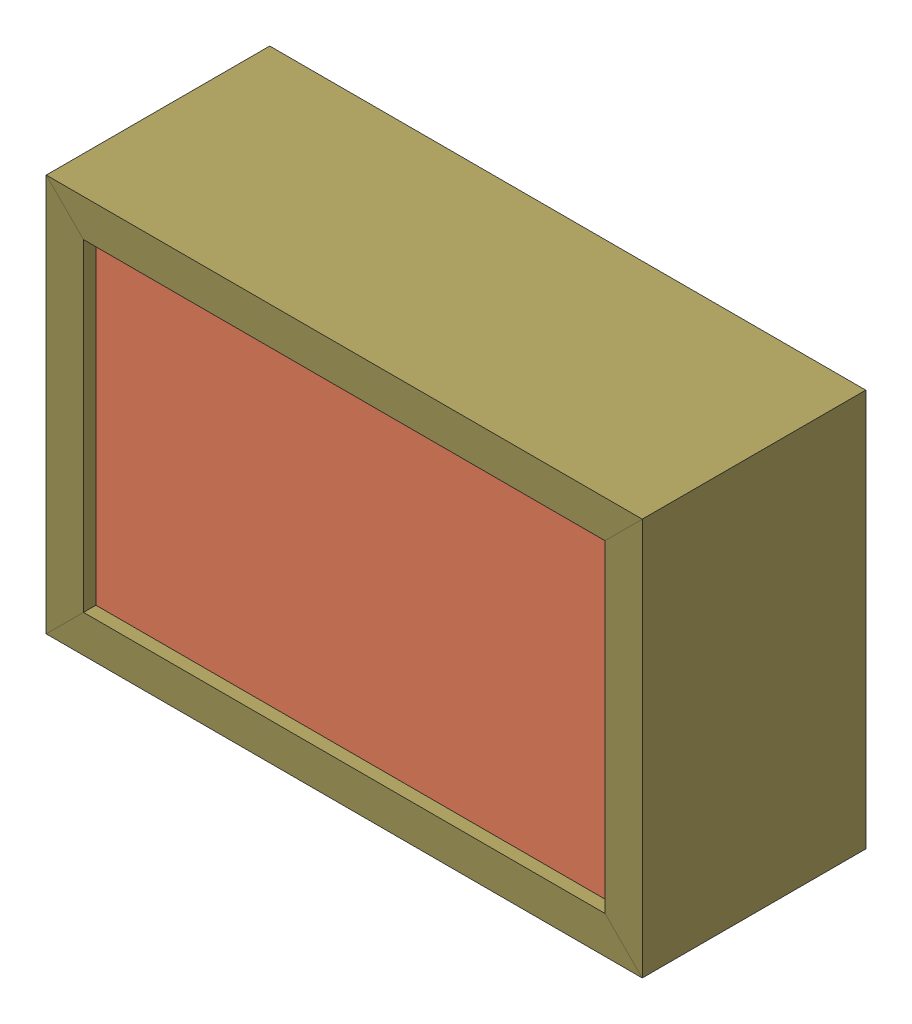
SolidWorks assembly Light Box Assembly, configuration Default. Lengths in mm.
Overall size (304.8 362.72 114.3).
32 component instances, 20 part files, 57 mates.
Components (placement in the parent):
- Paper Cutouts-1: Paper Cutouts [Sky Scrapers] at (-139.7 88.9003 -65.1157) size (279.4 177.8 38.2)
- Glass Panel-1: Glass Panel [Default] at (0 0 -16.9157) size (279.4 177.8 2.79)
- Screen Assembly v2-1: Screen Assembly v2 [Default] at (-1.8757 50.668 -76.7657) x (0.999835 0.01817 0) z (0 0 1) size (37.96 49.56 18.7)
  - Screen v2 PCB-1: Screen v2 PCB [34.5mm width] at origin size (34.5 47.27 1.65)
  - Straight Header - 1x8-1: Straight Header - 1x8 [Default] at (40.64 -21.385 0) size (20.12 2.54 10.71)
  - Led Panel-1: Led Panel [Default] at (0 7.815 4.65) size (35.48 36.23 5.6)
  - TFT panel-1: TFT panel [Default] at (0 9.085 10.15) size (27.82 32.57 1.5)
  - Part3^Screen Assembly v2-1: Part3^Screen Assembly v2 [Default] x (0 0 -1) z (1 0 0) size (10.1 5.32 20) (virtual)
  - Screen Bracket v2-1: Screen Bracket v2 [Default] at origin size (37.9 37.41 12.85)
- Servo Assembly-1: Servo Assembly [Default] at (-5.25 -52.55 -94.6407) x (-1 0 0) z (0 1 0) size (37.46 31.7 32.94) (flexible)
  - Servo Body-1: Servo Body [Valor predeterminado] at origin size (37.46 29.7 12)
  - Servo Horn-1: Servo Horn [Default] at (-42.7767 11.7 -5.0256) x (-0.01817 0 -0.999835) z (0.999835 0 -0.01817) size (32.8 4 7.8)
- 10mm MakerBeam-1: 10mm MakerBeam [Default] at (-0.5197 -23.9547 -75.9407) x (-0.999835 -0.01817 0) z (-0.01817 0.999835 0) size (10 10 90)
- Wooden Enclosure-1: Wooden Enclosure [Default] at (0 0 -122.0717) x (0 1 0) z (0 0 -1) size (362.72 304.8 114.3)
- Beam to Screen Bracket-1: Beam to Screen Bracket [Default] at (-1.3373 21.0379 -75.9407) x (-0.999835 -0.01817 0) z (-0.01817 0.999835 0) size (46.42 12 31.78)
- M3 Panhead Screw-1: M3 Panhead Screw [92000A118] at (-1.2464 16.0387 -75.9407) x (0.981612 0.017838 0.190052) z (-0.01817 0.999835 0) size (6 6 12.85)
- M2.5 Panhead Screw-1: M2.5 Panhead Screw [92000A105] at (17.6583 32.8849 -68.7657) x (0.01817 -0.999835 0) z (0 0 -1) size (5 5 12.45)
- Servo Mount-1: Servo Mount [Default] at (-5.25 -52.25 -91.6407) x (-1 0 0) z (0 0 1) size (41.46 36 35)
- M2.5 Panhead Screw-3: M2.5 Panhead Screw [92000A105] at (-0.2662 -37.9024 -74.9407) x (-0.976585 0.215134 0) z (0 0 -1) size (5 5 12.45)
- M2.5 Panhead Screw-4: M2.5 Panhead Screw [92000A105] at (0.2662 -67.1976 -74.9407) x (-0.976585 0.215134 0) z (0 0 -1) size (5 5 12.45)
- #6 Phillips Flathead Point .5in-1: #6 Phillips Flathead Point .5in [90048A148] at (9.98 -80.8443 -79.1407) x (0.64712 0 0.762388) z (0 1 0) size (6.65 6.65 15.24)
- #6 Phillips Flathead Point .5in-2: #6 Phillips Flathead Point .5in [90048A148] at (9.98 -80.8443 -101.1407) x (0.297443 0 -0.95474) z (0 1 0) size (6.65 6.65 15.24)
- #6 Phillips Flathead Point .5in-3: #6 Phillips Flathead Point .5in [90048A148] at (-20.48 -80.8443 -79.1407) x (0.64712 0 -0.762388) z (0 1 0) size (6.65 6.65 15.24)
- #6 Phillips Flathead Point .5in-4: #6 Phillips Flathead Point .5in [90048A148] at (-20.48 -80.8443 -101.1407) x (0.297443 0 0.95474) z (0 1 0) size (6.65 6.65 15.24)
- M2.5 Panhead Screw-5: M2.5 Panhead Screw [92000A105] at (8.48 -52.25 -89.0157) x (-0.89963 0.436653 0) z (0 0 -1) size (5 5 12.45)
- M2.5 Panhead Screw-8: M2.5 Panhead Screw [92000A105] at (-18.98 -52.25 -89.0157) x (0.89963 0.436653 0) z (0 0 -1) size (5 5 12.45)
- WS2812 Strip-1: WS2812 Strip [Default] at (-116.41 -82.55 -34.3657) size (249.45 2 10.1)
- WS2812 Strip-2: WS2812 Strip [Default] at (-116.41 -82.55 -47.0657) size (249.45 2 10.1)
- WS2812 Strip-3: WS2812 Strip [Default] at (-116.41 -82.55 -59.7657) size (249.45 2 10.1)
- Frame - Back Panel-1: Frame - Back Panel [Default] at (0 0 -122.0717) x (0 1 0) z (0 0 -1) size (183.53 285.12 6.35)
- Arrow Button-1: Arrow Button [Default] at (0 0 -115.7217) x (0 -1 0) z (0 0 1) size (26.33 13.17 9.09) (hidden)
- M2.5 Panhead Screw-9: M2.5 Panhead Screw [92000A105] at (-20.7508 32.187 -68.7657) x (-0.01817 0.999835 0) z (0 0 -1) size (5 5 12.45)
Mates (geometry in assembly coordinates):
- Symmetric1: symmetric: line of Paper Cutouts-1 through (-139.7 88.9003 -65.0157) axis (0 -1 0); line of Paper Cutouts-1 through (139.7 -88.9003 -65.0157) axis (0 1 0)
- Symmetric2: symmetric: line of Paper Cutouts-1 through (139.7 88.9003 -65.0157) axis (-1 0 0); line of Paper Cutouts-1 through (-139.7 -88.9003 -65.0157) axis (1 0 0)
- Coincident4: coincident: plane of Glass Panel-1 through (0 0 -16.9157) normal (1 0 0); plane of assembly through (0 0 0) normal (1 0 0)
- Coincident5: coincident: plane of Glass Panel-1 through (0 0 -16.9157) normal (0 1 0); plane of assembly through (0 0 0) normal (0 1 0)
- Distance1: distance = 10 mm: plane of Glass Panel-1 through (0 0 -16.9157) normal (0 0 -1); plane of Paper Cutouts-1 through (137.2622 -24.4631 -26.9157) normal (0 0 1)
- Coincident6: coincident: plane of Paper Cutouts-1 through (-139.7 88.9003 -65.1157) normal (0 0 -1); plane of Screen Assembly v2-1/TFT panel-1 through (-2.0408 59.7515 -65.1157) normal (0 0 1)
- Coincident7: coincident: plane of Glass Panel-1 through (0 0 -1.0858) normal (0 0 1); plane of assembly through (0 0 0) normal (0 0 1)
- Coincident9: coincident: plane of Servo Assembly-1/Servo Horn-1 through (0 -52.55 -80.9407) normal (0 0 1); plane of 10mm MakerBeam-1 through (-0.5197 -23.9547 -80.9407) normal (0 0 -1)
- Coincident10: coincident: line of Servo Assembly-1/Servo Horn-1 through (-0.2662 -37.9024 -80.9407) axis (0.01817 -0.999835 0); plane of 10mm MakerBeam-1 through (-0.5197 -23.9547 -75.9407) normal (-0.999835 -0.01817 0)
- Tangent1: tangent: cylinder of Servo Assembly-1/Servo Horn-1 through (0.2662 -67.1976 -80.9407) axis (0 0 -1) radius 1.75; plane of 10mm MakerBeam-1 through (-4.7012 -69.0381 -80.9407) normal (0.01817 -0.999835 0)
- Width1: width: plane of 10mm MakerBeam-1 through (-6.3365 20.947 -80.9407) normal (-0.999835 -0.01817 0); plane of 10mm MakerBeam-1 through (5.2972 -68.8564 -80.9407) normal (0.999835 0.01817 0); plane of ? through (-21.5393 89.7587 -65.6157) normal (-0.999835 -0.01817 0); plane of ? through (16.3545 90.4473 -65.6157) normal (0.999835 0.01817 0)
- InPlace2: in place: plane of ? through (0 -63.79 -93.075) normal (0 0 -1); plane of ? through (0 0 -93.075) normal (0 0 -1); moOrthogonalPlaneRef_w of ? through (0 -63.79 -93.075) normal (0 0 -1); plane of ? through (0 0 -93.075) normal (0 1 0); plane of ? through (0 -63.79 -93.075) normal (0 0 -1); plane of ? through (0 0 -93.075) normal (-1 0 0); plane of ? through (-5.25 -52.55 -99.6048) normal (0 0 -1); unknown of ?
- Coincident16: coincident: 
- Coincident17: coincident: unknown of ?; plane of ? through (0 0 -109.0358) normal (1 0 0)
- Coincident18: coincident: unknown of ?; plane of ? through (0 0 -109.0358) normal (0 1 0)
- Width2: width: plane of 10mm MakerBeam-1 through (-0.5197 -23.9547 -80.9407) normal (0 0 -1); plane of 10mm MakerBeam-1 through (-0.5197 -23.9547 -70.9407) normal (0 0 1); plane of ? through (-1.8757 50.668 -75.1157) normal (0 0 1); plane of ? through (-1.8757 50.668 -76.7657) normal (0 0 -1)
- Distance4: distance = 6 mm: plane of ? through (15.8009 27.3503 -75.1157) normal (0.01817 -0.999835 0); plane of 10mm MakerBeam-1 through (3.6619 21.1287 -80.9407) normal (-0.01817 0.999835 0)
- InPlace3: in place: plane of ? through (5 10.06 -63.55) normal (0 1 0); plane of ? through (0 10.06 0) normal (0 1 0); plane of ? through (5 10.06 -63.55) normal (0 1 0); plane of ? through (0 10.06 0) normal (0 0 -1); plane of ? through (5 10.06 -63.55) normal (0 1 0); plane of ? through (0 10.06 0) normal (1 0 0); plane of 10mm MakerBeam-1 through (3.6619 21.1287 -80.9407) normal (-0.01817 0.999835 0); unknown of Beam to Screen Bracket-1
- Coincident18: coincident: 
- Coincident19: coincident: plane of 10mm MakerBeam-1 through (-1.3373 21.0379 -75.9407) normal (0 0 1); plane of Beam to Screen Bracket-1 through (-1.3373 21.0379 -75.9407) normal (0 0 1)
- Coincident20: coincident: unknown of 10mm MakerBeam-1; plane of Beam to Screen Bracket-1 through (-1.3373 21.0379 -75.9407) normal (-0.999835 -0.01817 0)
- Concentric1: concentric: circle of 10mm MakerBeam-1; circle of M3 Panhead Screw-1
- Coincident22: coincident: plane of ? through (-1.8757 50.668 -76.7657) normal (0 0 -1); plane of M2.5 Panhead Screw-1 through (17.6583 32.8849 -76.7657) normal (0 0 1)
- Concentric2: concentric: circle of ?; circle of M2.5 Panhead Screw-1
- Coincident24: coincident: plane of Beam to Screen Bracket-1 through (3.6074 24.1282 -80.9407) normal (-0.01817 0.999835 0); plane of M3 Panhead Screw-1 through (-1.3918 24.0374 -75.9407) normal (0.01817 -0.999835 0)
- Distance5: distance = 6.35 mm: plane of Wooden Enclosure-1 through (0 0 -7.7717) normal (0 0 1); plane of Glass Panel-1 through (0 0 -14.1217) normal (0 0 1)
- Coincident25: coincident: plane of Wooden Enclosure-1 through (0 0 -122.0717) normal (1 0 0); plane of assembly through (0 0 0) normal (1 0 0)
- Width3: width: plane of ? through (133.35 -82.55 -7.7717) normal (0 1 0); plane of ? through (-133.35 82.55 -7.7717) normal (0 -1 0); plane of Glass Panel-1 through (-139.7 88.9 -14.1217) normal (0 1 0); plane of Glass Panel-1 through (-139.7 -88.9 -14.1217) normal (0 -1 0)
- Distance6: distance = 30 mm: line of Servo Assembly-1/Servo Body-1 through (0 -52.55 -82.9407) axis (0 0 -1); plane of Wooden Enclosure-1 through (133.35 -82.55 -7.7717) normal (0 1 0)
- Coincident28: coincident: line of Servo Assembly-1/Servo Body-1 through (0 -52.55 -82.9407) axis (0 0 -1)
- Parallel2: parallel: plane of Servo Assembly-1/Servo Body-1 through (6 -58.55 -112.6407) normal (0 -1 0); plane of Wooden Enclosure-1 through (133.35 -82.55 -7.7717) normal (0 1 0)
- Concentric4: concentric: circle of Servo Assembly-1/Servo Horn-1; circle of M2.5 Panhead Screw-3
- Coincident29: coincident: plane of Servo Assembly-1/Servo Horn-1 through (0.2662 -67.1976 -82.9407) normal (0 0 -1); plane of M2.5 Panhead Screw-3 through (-0.2662 -37.9024 -82.9407) normal (0 0 1)
- Coincident30: coincident: plane of Servo Assembly-1/Servo Horn-1 through (0.2662 -67.1976 -82.9407) normal (0 0 -1); plane of M2.5 Panhead Screw-4 through (0.2662 -67.1976 -82.9407) normal (0 0 1)
- Concentric5: concentric: circle of Servo Assembly-1/Servo Horn-1; circle of M2.5 Panhead Screw-4
- Concentric6: concentric: circle of Servo Mount-1; circle of #6 Phillips Flathead Point .5in-1
- Coincident31: coincident: cone of Servo Mount-1 through (9.98 -78.25 -79.1407) axis (0 -1 0); cylinder of #6 Phillips Flathead Point .5in-1 through (9.98 -78.7361 -79.1407) axis (0 -1 0) radius 715.585
- Coincident32: coincident: cylinder of Servo Mount-1 through (9.98 -80.5507 -101.1407) axis (0 -1 0) radius 715.585; cylinder of #6 Phillips Flathead Point .5in-2 through (9.98 -78.7361 -101.1407) axis (0 -1 0) radius 715.585
- Coincident33: coincident: plane of Servo Assembly-1/Servo Body-1 through (8.725 -52.55 -97.0157) normal (0 0 -1); plane of M2.5 Panhead Screw-5 through (8.48 -52.25 -97.0157) normal (0 0 1)
- Concentric8: concentric: circle of Servo Mount-1; circle of M2.5 Panhead Screw-5
- Coincident37: coincident: plane of WS2812 Strip-1 through (0 -82.55 -34.3657) normal (-1 0 0); plane of assembly through (0 0 0) normal (1 0 0)
- Distance7: distance = 0.2 mm: plane of WS2812 Strip-1 through (-124.725 -82.05 -39.4157) normal (0 0 -1); plane of Paper Cutouts-1 through (-86.2566 -4.1633 -39.6157) normal (0 0 1)
- Coincident39: coincident: plane of Wooden Enclosure-1 through (133.35 -82.55 -7.7717) normal (0 1 0); plane of WS2812 Strip-1 through (-116.41 -82.55 -34.3657) normal (0 -1 0)
- Coincident40: coincident: plane of Glass Panel-1 through (0 0 -14.1217) normal (0 0 1); plane of Wooden Enclosure-1 through (0 -92.075 -14.1217) normal (0 0 -1)
- Coincident41: coincident: plane of Servo Assembly-1/Servo Body-1 through (8.725 -52.55 -94.6407) normal (0 0 1); plane of Servo Mount-1 through (-5.25 -52.25 -94.6407) normal (0 0 -1)
- Coincident42: coincident: plane of Servo Assembly-1/Servo Body-1 through (-5.25 -52.55 -94.6407) normal (-1 0 0); plane of Servo Mount-1 through (-5.25 -52.25 -91.6407) normal (-1 0 0)
- Coincident43: coincident: plane of Servo Assembly-1/Servo Body-1 through (6 -58.55 -112.6407) normal (0 -1 0); plane of Servo Mount-1 through (-16.7 -58.55 -88.6407) normal (0 1 0)
- InPlace9: in place: plane of ? through (0 0 -109.0358) normal (0 0 -1); plane of ? through (0 0 -109.0358) normal (0 0 -1); plane of ? through (0 0 -109.0358) normal (0 0 -1); plane of ? through (0 0 -109.0358) normal (0 1 0); plane of ? through (0 0 -109.0358) normal (0 0 -1); plane of ? through (0 0 -109.0358) normal (-1 0 0); plane of ? through (0 0 -122.0717) normal (0 0 -1); unknown of ?
- Coincident44: coincident: 
- Coincident45: coincident: plane of ? through (0 0 -122.0717) normal (1 0 0); plane of ? through (0 0 -122.0717) normal (1 0 0)
- Coincident46: coincident: plane of ? through (0 0 -122.0717) normal (0 -1 0); plane of ? through (0 0 -122.0717) normal (0 1 0)
- InPlace11: in place: plane of ? through (0 0 -119.8785) normal (0 0 1); plane of ? through (0 0 -119.8785) normal (0 0 1); plane of ? through (0 0 -119.8785) normal (0 0 1); plane of ? through (0 0 -119.8785) normal (0 1 0); plane of ? through (0 0 -119.8785) normal (0 0 1); plane of ? through (0 0 -119.8785) normal (1 0 0); plane of ? through (0 0 -115.7217) normal (0 0 1); unknown of Arrow Button-1
- Coincident47: coincident: 
- Coincident48: coincident: plane of ? through (0 0 -115.7217) normal (1 0 0); plane of Arrow Button-1 through (0 0 -115.7217) normal (1 0 0)
- Coincident49: coincident: plane of ? through (0 0 -115.7217) normal (0 1 0); plane of Arrow Button-1 through (0 0 -115.7217) normal (0 -1 0)
- Distance8: distance = 5.5 mm: plane of M2.5 Panhead Screw-1 through (17.6583 32.8849 -68.7657) normal (0.01817 -0.999835 0); plane of ? through (15.8009 27.3503 -75.1157) normal (0.01817 -0.999835 0)
- Distance9: distance = 1 mm: plane of ? through (15.8009 27.3503 -75.1157) normal (0.999835 0.01817 0); line of M2.5 Panhead Screw-1 through (16.7008 32.8675 -68.7657) axis (0 0 -1)
